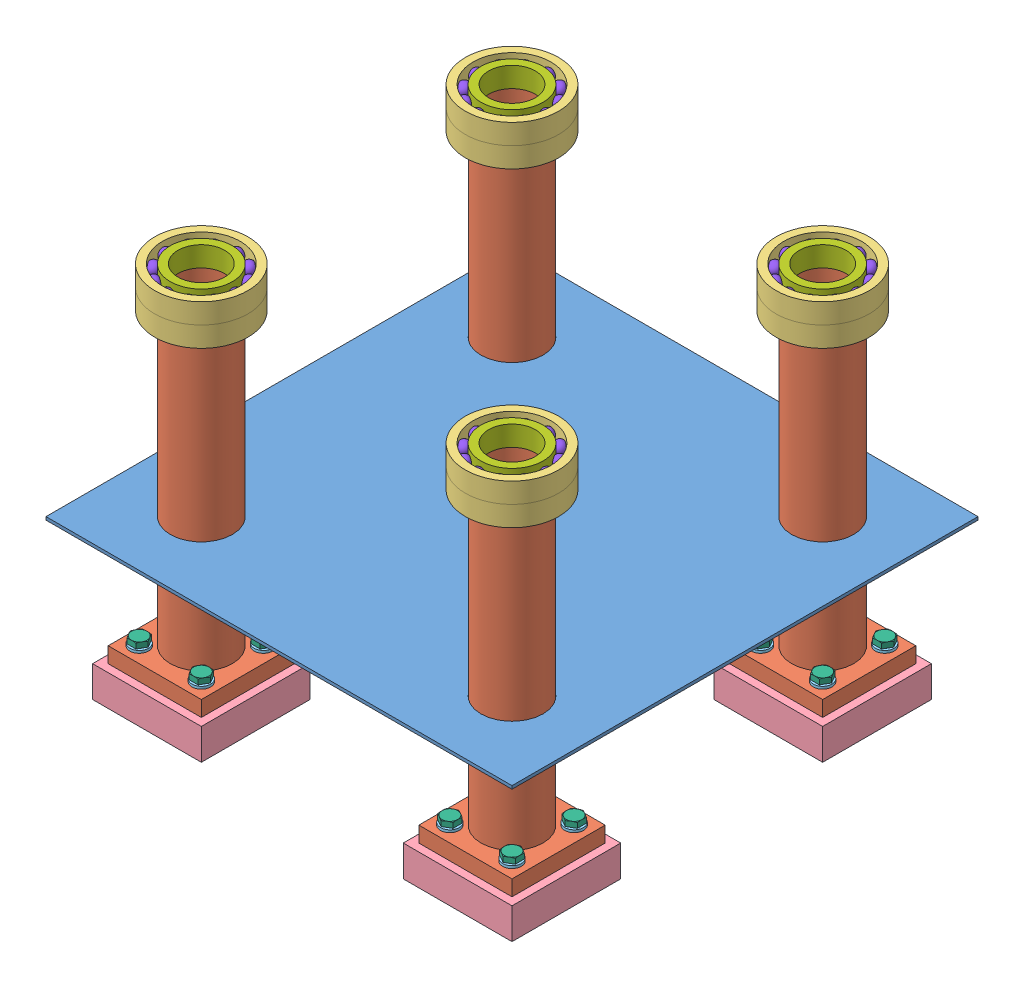
SolidWorks assembly BE101-01Z-01Z 四柱总装, configuration 默认. Lengths in mm.
Overall size (300 243 300).
113 component instances, 8 part files, 6 mates.
Components (placement in the parent):
- BE101-01Z-003 四孔平板-1: BE101-01Z-003 四孔平板 [默认] at origin size (300 2 300)
- BE101-01Z-02Z 立柱套装-1: BE101-01Z-02Z 立柱套装 [默认] at (100 -72 -100) size (70 243 70)
  - BE101-01Z-04Z 烟囱与圈-1: BE101-01Z-04Z 烟囱与圈 [默认] at origin size (60 210 60)
    - BE101-01Z-004 中空立柱-1: BE101-01Z-004 中空立柱 [默认] at origin size (60 210 60)
    - BE101-01Z-006 轴承外圈-1: BE101-01Z-006 轴承外圈 [默认] at (0 193.5 0) size (60 13 60)
  - BE101-01Z-005 四眼小板-1: BE101-01Z-005 四眼小板 [默认] at (0 -30 0) size (70 20 70)
  - plain washers--product grade c gb-1: plain washers--product grade c gb [GB_FASTENER_WASHER_SMWC 6] at (20 1.6 -20) x (1 0 0) z (0 1 0) size (12 12 1.6)
  - hex head bolts-full thread grade c gb-1: hex head bolts-full thread grade c gb [GB_FASTENER_BOLT_HHBFTC M6X20-N] at (20 5.6 -20) x (0 -1 0) z (0 0 1) size (24 11.55 10)
  - plain washers--product grade c gb-2: plain washers--product grade c gb [GB_FASTENER_WASHER_SMWC 6] at (20 1.6 20) x (1 0 0) z (0 1 0) size (12 12 1.6)
  - plain washers--product grade c gb-3: plain washers--product grade c gb [GB_FASTENER_WASHER_SMWC 6] at (-20 1.6 20) x (1 0 0) z (0 1 0) size (12 12 1.6)
  - plain washers--product grade c gb-4: plain washers--product grade c gb [GB_FASTENER_WASHER_SMWC 6] at (-20 1.6 -20) x (1 0 0) z (0 1 0) size (12 12 1.6)
  - hex head bolts-full thread grade c gb-2: hex head bolts-full thread grade c gb [GB_FASTENER_BOLT_HHBFTC M6X20-N] at (20 5.6 20) x (0 -1 0) z (0 0 1) size (24 11.55 10)
  - hex head bolts-full thread grade c gb-3: hex head bolts-full thread grade c gb [GB_FASTENER_BOLT_HHBFTC M6X20-N] at (-20 5.6 20) x (0 -1 0) z (0 0 1) size (24 11.55 10)
  - hex head bolts-full thread grade c gb-4: hex head bolts-full thread grade c gb [GB_FASTENER_BOLT_HHBFTC M6X20-N] at (-20 5.6 -20) x (0 -1 0) z (0 0 1) size (24 11.55 10)
  - BE101-01Z-03Z 滚珠轴承-1: BE101-01Z-03Z 滚珠轴承 [默认] at (0 206.5 0) size (60 13 60)
    - BE101-01Z-007 轴承内圈-1: BE101-01Z-007 轴承内圈 [默认] at origin size (40 13 40)
    - BE101-01Z-006 轴承外圈-1: BE101-01Z-006 轴承外圈 [默认] at origin size (60 13 60)
    - BE101-01Z-008 轴承滚珠-1: BE101-01Z-008 轴承滚珠 [默认] at (0 0 -22.5) size (8 8 8)
    - BE101-01Z-008 轴承滚珠-2: BE101-01Z-008 轴承滚珠 [默认] at (11.25 0 -19.4856) x (0.866025 0 0.5) z (-0.5 0 0.866025) size (8 8 8)
    - BE101-01Z-008 轴承滚珠-3: BE101-01Z-008 轴承滚珠 [默认] at (19.4856 0 -11.25) x (0.5 0 0.866025) z (-0.866025 0 0.5) size (8 8 8)
    - BE101-01Z-008 轴承滚珠-4: BE101-01Z-008 轴承滚珠 [默认] at (22.5 0 0) x (0 0 1) z (-1 0 0) size (8 8 8)
    - BE101-01Z-008 轴承滚珠-5: BE101-01Z-008 轴承滚珠 [默认] at (19.4856 0 11.25) x (-0.5 0 0.866025) z (-0.866025 0 -0.5) size (8 8 8)
    - BE101-01Z-008 轴承滚珠-6: BE101-01Z-008 轴承滚珠 [默认] at (11.25 0 19.4856) x (-0.866025 0 0.5) z (-0.5 0 -0.866025) size (8 8 8)
    - BE101-01Z-008 轴承滚珠-7: BE101-01Z-008 轴承滚珠 [默认] at (0 0 22.5) x (-1 0 0) z (0 0 -1) size (8 8 8)
    - BE101-01Z-008 轴承滚珠-8: BE101-01Z-008 轴承滚珠 [默认] at (-11.25 0 19.4856) x (-0.866025 0 -0.5) z (0.5 0 -0.866025) size (8 8 8)
    - BE101-01Z-008 轴承滚珠-9: BE101-01Z-008 轴承滚珠 [默认] at (-19.4856 0 11.25) x (-0.5 0 -0.866025) z (0.866025 0 -0.5) size (8 8 8)
    - BE101-01Z-008 轴承滚珠-10: BE101-01Z-008 轴承滚珠 [默认] at (-22.5 0 0) x (0 0 -1) z (1 0 0) size (8 8 8)
    - BE101-01Z-008 轴承滚珠-11: BE101-01Z-008 轴承滚珠 [默认] at (-19.4856 0 -11.25) x (0.5 0 -0.866025) z (0.866025 0 0.5) size (8 8 8)
    - BE101-01Z-008 轴承滚珠-12: BE101-01Z-008 轴承滚珠 [默认] at (-11.25 0 -19.4856) x (0.866025 0 -0.5) z (0.5 0 0.866025) size (8 8 8)
- BE101-01Z-02Z 立柱套装-6: BE101-01Z-02Z 立柱套装 [默认] at (100 -72 100) x (0 0 1) z (-1 0 0) size (70 243 70)
  - BE101-01Z-04Z 烟囱与圈-1: BE101-01Z-04Z 烟囱与圈 [默认] at origin size (60 210 60)
    - BE101-01Z-004 中空立柱-1: BE101-01Z-004 中空立柱 [默认] at origin size (60 210 60)
    - BE101-01Z-006 轴承外圈-1: BE101-01Z-006 轴承外圈 [默认] at (0 193.5 0) size (60 13 60)
  - BE101-01Z-005 四眼小板-1: BE101-01Z-005 四眼小板 [默认] at (0 -30 0) size (70 20 70)
  - plain washers--product grade c gb-1: plain washers--product grade c gb [GB_FASTENER_WASHER_SMWC 6] at (20 1.6 -20) x (1 0 0) z (0 1 0) size (12 12 1.6)
  - hex head bolts-full thread grade c gb-1: hex head bolts-full thread grade c gb [GB_FASTENER_BOLT_HHBFTC M6X20-N] at (20 5.6 -20) x (0 -1 0) z (0 0 1) size (24 11.55 10)
  - plain washers--product grade c gb-2: plain washers--product grade c gb [GB_FASTENER_WASHER_SMWC 6] at (20 1.6 20) x (1 0 0) z (0 1 0) size (12 12 1.6)
  - plain washers--product grade c gb-3: plain washers--product grade c gb [GB_FASTENER_WASHER_SMWC 6] at (-20 1.6 20) x (1 0 0) z (0 1 0) size (12 12 1.6)
  - plain washers--product grade c gb-4: plain washers--product grade c gb [GB_FASTENER_WASHER_SMWC 6] at (-20 1.6 -20) x (1 0 0) z (0 1 0) size (12 12 1.6)
  - hex head bolts-full thread grade c gb-2: hex head bolts-full thread grade c gb [GB_FASTENER_BOLT_HHBFTC M6X20-N] at (20 5.6 20) x (0 -1 0) z (0 0 1) size (24 11.55 10)
  - hex head bolts-full thread grade c gb-3: hex head bolts-full thread grade c gb [GB_FASTENER_BOLT_HHBFTC M6X20-N] at (-20 5.6 20) x (0 -1 0) z (0 0 1) size (24 11.55 10)
  - hex head bolts-full thread grade c gb-4: hex head bolts-full thread grade c gb [GB_FASTENER_BOLT_HHBFTC M6X20-N] at (-20 5.6 -20) x (0 -1 0) z (0 0 1) size (24 11.55 10)
  - BE101-01Z-03Z 滚珠轴承-1: BE101-01Z-03Z 滚珠轴承 [默认] at (0 206.5 0) size (60 13 60)
    - BE101-01Z-007 轴承内圈-1: BE101-01Z-007 轴承内圈 [默认] at origin size (40 13 40)
    - BE101-01Z-006 轴承外圈-1: BE101-01Z-006 轴承外圈 [默认] at origin size (60 13 60)
    - BE101-01Z-008 轴承滚珠-1: BE101-01Z-008 轴承滚珠 [默认] at (0 0 -22.5) size (8 8 8)
    - BE101-01Z-008 轴承滚珠-2: BE101-01Z-008 轴承滚珠 [默认] at (11.25 0 -19.4856) x (0.866025 0 0.5) z (-0.5 0 0.866025) size (8 8 8)
    - BE101-01Z-008 轴承滚珠-3: BE101-01Z-008 轴承滚珠 [默认] at (19.4856 0 -11.25) x (0.5 0 0.866025) z (-0.866025 0 0.5) size (8 8 8)
    - BE101-01Z-008 轴承滚珠-4: BE101-01Z-008 轴承滚珠 [默认] at (22.5 0 0) x (0 0 1) z (-1 0 0) size (8 8 8)
    - BE101-01Z-008 轴承滚珠-5: BE101-01Z-008 轴承滚珠 [默认] at (19.4856 0 11.25) x (-0.5 0 0.866025) z (-0.866025 0 -0.5) size (8 8 8)
    - BE101-01Z-008 轴承滚珠-6: BE101-01Z-008 轴承滚珠 [默认] at (11.25 0 19.4856) x (-0.866025 0 0.5) z (-0.5 0 -0.866025) size (8 8 8)
    - BE101-01Z-008 轴承滚珠-7: BE101-01Z-008 轴承滚珠 [默认] at (0 0 22.5) x (-1 0 0) z (0 0 -1) size (8 8 8)
    - BE101-01Z-008 轴承滚珠-8: BE101-01Z-008 轴承滚珠 [默认] at (-11.25 0 19.4856) x (-0.866025 0 -0.5) z (0.5 0 -0.866025) size (8 8 8)
    - BE101-01Z-008 轴承滚珠-9: BE101-01Z-008 轴承滚珠 [默认] at (-19.4856 0 11.25) x (-0.5 0 -0.866025) z (0.866025 0 -0.5) size (8 8 8)
    - BE101-01Z-008 轴承滚珠-10: BE101-01Z-008 轴承滚珠 [默认] at (-22.5 0 0) x (0 0 -1) z (1 0 0) size (8 8 8)
    - BE101-01Z-008 轴承滚珠-11: BE101-01Z-008 轴承滚珠 [默认] at (-19.4856 0 -11.25) x (0.5 0 -0.866025) z (0.866025 0 0.5) size (8 8 8)
    - BE101-01Z-008 轴承滚珠-12: BE101-01Z-008 轴承滚珠 [默认] at (-11.25 0 -19.4856) x (0.866025 0 -0.5) z (0.5 0 0.866025) size (8 8 8)
- BE101-01Z-02Z 立柱套装-7: BE101-01Z-02Z 立柱套装 [默认] at (-100 -72 100) x (-1 0 0) z (0 0 -1) size (70 243 70)
  - BE101-01Z-04Z 烟囱与圈-1: BE101-01Z-04Z 烟囱与圈 [默认] at origin size (60 210 60)
    - BE101-01Z-004 中空立柱-1: BE101-01Z-004 中空立柱 [默认] at origin size (60 210 60)
    - BE101-01Z-006 轴承外圈-1: BE101-01Z-006 轴承外圈 [默认] at (0 193.5 0) size (60 13 60)
  - BE101-01Z-005 四眼小板-1: BE101-01Z-005 四眼小板 [默认] at (0 -30 0) size (70 20 70)
  - plain washers--product grade c gb-1: plain washers--product grade c gb [GB_FASTENER_WASHER_SMWC 6] at (20 1.6 -20) x (1 0 0) z (0 1 0) size (12 12 1.6)
  - hex head bolts-full thread grade c gb-1: hex head bolts-full thread grade c gb [GB_FASTENER_BOLT_HHBFTC M6X20-N] at (20 5.6 -20) x (0 -1 0) z (0 0 1) size (24 11.55 10)
  - plain washers--product grade c gb-2: plain washers--product grade c gb [GB_FASTENER_WASHER_SMWC 6] at (20 1.6 20) x (1 0 0) z (0 1 0) size (12 12 1.6)
  - plain washers--product grade c gb-3: plain washers--product grade c gb [GB_FASTENER_WASHER_SMWC 6] at (-20 1.6 20) x (1 0 0) z (0 1 0) size (12 12 1.6)
  - plain washers--product grade c gb-4: plain washers--product grade c gb [GB_FASTENER_WASHER_SMWC 6] at (-20 1.6 -20) x (1 0 0) z (0 1 0) size (12 12 1.6)
  - hex head bolts-full thread grade c gb-2: hex head bolts-full thread grade c gb [GB_FASTENER_BOLT_HHBFTC M6X20-N] at (20 5.6 20) x (0 -1 0) z (0 0 1) size (24 11.55 10)
  - hex head bolts-full thread grade c gb-3: hex head bolts-full thread grade c gb [GB_FASTENER_BOLT_HHBFTC M6X20-N] at (-20 5.6 20) x (0 -1 0) z (0 0 1) size (24 11.55 10)
  - hex head bolts-full thread grade c gb-4: hex head bolts-full thread grade c gb [GB_FASTENER_BOLT_HHBFTC M6X20-N] at (-20 5.6 -20) x (0 -1 0) z (0 0 1) size (24 11.55 10)
  - BE101-01Z-03Z 滚珠轴承-1: BE101-01Z-03Z 滚珠轴承 [默认] at (0 206.5 0) size (60 13 60)
    - BE101-01Z-007 轴承内圈-1: BE101-01Z-007 轴承内圈 [默认] at origin size (40 13 40)
    - BE101-01Z-006 轴承外圈-1: BE101-01Z-006 轴承外圈 [默认] at origin size (60 13 60)
    - BE101-01Z-008 轴承滚珠-1: BE101-01Z-008 轴承滚珠 [默认] at (0 0 -22.5) size (8 8 8)
    - BE101-01Z-008 轴承滚珠-2: BE101-01Z-008 轴承滚珠 [默认] at (11.25 0 -19.4856) x (0.866025 0 0.5) z (-0.5 0 0.866025) size (8 8 8)
    - BE101-01Z-008 轴承滚珠-3: BE101-01Z-008 轴承滚珠 [默认] at (19.4856 0 -11.25) x (0.5 0 0.866025) z (-0.866025 0 0.5) size (8 8 8)
    - BE101-01Z-008 轴承滚珠-4: BE101-01Z-008 轴承滚珠 [默认] at (22.5 0 0) x (0 0 1) z (-1 0 0) size (8 8 8)
    - BE101-01Z-008 轴承滚珠-5: BE101-01Z-008 轴承滚珠 [默认] at (19.4856 0 11.25) x (-0.5 0 0.866025) z (-0.866025 0 -0.5) size (8 8 8)
    - BE101-01Z-008 轴承滚珠-6: BE101-01Z-008 轴承滚珠 [默认] at (11.25 0 19.4856) x (-0.866025 0 0.5) z (-0.5 0 -0.866025) size (8 8 8)
    - BE101-01Z-008 轴承滚珠-7: BE101-01Z-008 轴承滚珠 [默认] at (0 0 22.5) x (-1 0 0) z (0 0 -1) size (8 8 8)
    - BE101-01Z-008 轴承滚珠-8: BE101-01Z-008 轴承滚珠 [默认] at (-11.25 0 19.4856) x (-0.866025 0 -0.5) z (0.5 0 -0.866025) size (8 8 8)
    - BE101-01Z-008 轴承滚珠-9: BE101-01Z-008 轴承滚珠 [默认] at (-19.4856 0 11.25) x (-0.5 0 -0.866025) z (0.866025 0 -0.5) size (8 8 8)
    - BE101-01Z-008 轴承滚珠-10: BE101-01Z-008 轴承滚珠 [默认] at (-22.5 0 0) x (0 0 -1) z (1 0 0) size (8 8 8)
    - BE101-01Z-008 轴承滚珠-11: BE101-01Z-008 轴承滚珠 [默认] at (-19.4856 0 -11.25) x (0.5 0 -0.866025) z (0.866025 0 0.5) size (8 8 8)
    - BE101-01Z-008 轴承滚珠-12: BE101-01Z-008 轴承滚珠 [默认] at (-11.25 0 -19.4856) x (0.866025 0 -0.5) z (0.5 0 0.866025) size (8 8 8)
- BE101-01Z-02Z 立柱套装-8: BE101-01Z-02Z 立柱套装 [默认] at (-100 -72 -100) x (0 0 -1) z (1 0 0) size (70 243 70)
  - BE101-01Z-04Z 烟囱与圈-1: BE101-01Z-04Z 烟囱与圈 [默认] at origin size (60 210 60)
    - BE101-01Z-004 中空立柱-1: BE101-01Z-004 中空立柱 [默认] at origin size (60 210 60)
    - BE101-01Z-006 轴承外圈-1: BE101-01Z-006 轴承外圈 [默认] at (0 193.5 0) size (60 13 60)
  - BE101-01Z-005 四眼小板-1: BE101-01Z-005 四眼小板 [默认] at (0 -30 0) size (70 20 70)
  - plain washers--product grade c gb-1: plain washers--product grade c gb [GB_FASTENER_WASHER_SMWC 6] at (20 1.6 -20) x (1 0 0) z (0 1 0) size (12 12 1.6)
  - hex head bolts-full thread grade c gb-1: hex head bolts-full thread grade c gb [GB_FASTENER_BOLT_HHBFTC M6X20-N] at (20 5.6 -20) x (0 -1 0) z (0 0 1) size (24 11.55 10)
  - plain washers--product grade c gb-2: plain washers--product grade c gb [GB_FASTENER_WASHER_SMWC 6] at (20 1.6 20) x (1 0 0) z (0 1 0) size (12 12 1.6)
  - plain washers--product grade c gb-3: plain washers--product grade c gb [GB_FASTENER_WASHER_SMWC 6] at (-20 1.6 20) x (1 0 0) z (0 1 0) size (12 12 1.6)
  - plain washers--product grade c gb-4: plain washers--product grade c gb [GB_FASTENER_WASHER_SMWC 6] at (-20 1.6 -20) x (1 0 0) z (0 1 0) size (12 12 1.6)
  - hex head bolts-full thread grade c gb-2: hex head bolts-full thread grade c gb [GB_FASTENER_BOLT_HHBFTC M6X20-N] at (20 5.6 20) x (0 -1 0) z (0 0 1) size (24 11.55 10)
  - hex head bolts-full thread grade c gb-3: hex head bolts-full thread grade c gb [GB_FASTENER_BOLT_HHBFTC M6X20-N] at (-20 5.6 20) x (0 -1 0) z (0 0 1) size (24 11.55 10)
  - hex head bolts-full thread grade c gb-4: hex head bolts-full thread grade c gb [GB_FASTENER_BOLT_HHBFTC M6X20-N] at (-20 5.6 -20) x (0 -1 0) z (0 0 1) size (24 11.55 10)
  - BE101-01Z-03Z 滚珠轴承-1: BE101-01Z-03Z 滚珠轴承 [默认] at (0 206.5 0) size (60 13 60)
    - BE101-01Z-007 轴承内圈-1: BE101-01Z-007 轴承内圈 [默认] at origin size (40 13 40)
    - BE101-01Z-006 轴承外圈-1: BE101-01Z-006 轴承外圈 [默认] at origin size (60 13 60)
    - BE101-01Z-008 轴承滚珠-1: BE101-01Z-008 轴承滚珠 [默认] at (0 0 -22.5) size (8 8 8)
    - BE101-01Z-008 轴承滚珠-2: BE101-01Z-008 轴承滚珠 [默认] at (11.25 0 -19.4856) x (0.866025 0 0.5) z (-0.5 0 0.866025) size (8 8 8)
    - BE101-01Z-008 轴承滚珠-3: BE101-01Z-008 轴承滚珠 [默认] at (19.4856 0 -11.25) x (0.5 0 0.866025) z (-0.866025 0 0.5) size (8 8 8)
    - BE101-01Z-008 轴承滚珠-4: BE101-01Z-008 轴承滚珠 [默认] at (22.5 0 0) x (0 0 1) z (-1 0 0) size (8 8 8)
    - BE101-01Z-008 轴承滚珠-5: BE101-01Z-008 轴承滚珠 [默认] at (19.4856 0 11.25) x (-0.5 0 0.866025) z (-0.866025 0 -0.5) size (8 8 8)
    - BE101-01Z-008 轴承滚珠-6: BE101-01Z-008 轴承滚珠 [默认] at (11.25 0 19.4856) x (-0.866025 0 0.5) z (-0.5 0 -0.866025) size (8 8 8)
    - BE101-01Z-008 轴承滚珠-7: BE101-01Z-008 轴承滚珠 [默认] at (0 0 22.5) x (-1 0 0) z (0 0 -1) size (8 8 8)
    - BE101-01Z-008 轴承滚珠-8: BE101-01Z-008 轴承滚珠 [默认] at (-11.25 0 19.4856) x (-0.866025 0 -0.5) z (0.5 0 -0.866025) size (8 8 8)
    - BE101-01Z-008 轴承滚珠-9: BE101-01Z-008 轴承滚珠 [默认] at (-19.4856 0 11.25) x (-0.5 0 -0.866025) z (0.866025 0 -0.5) size (8 8 8)
    - BE101-01Z-008 轴承滚珠-10: BE101-01Z-008 轴承滚珠 [默认] at (-22.5 0 0) x (0 0 -1) z (1 0 0) size (8 8 8)
    - BE101-01Z-008 轴承滚珠-11: BE101-01Z-008 轴承滚珠 [默认] at (-19.4856 0 -11.25) x (0.5 0 -0.866025) z (0.866025 0 0.5) size (8 8 8)
    - BE101-01Z-008 轴承滚珠-12: BE101-01Z-008 轴承滚珠 [默认] at (-11.25 0 -19.4856) x (0.866025 0 -0.5) z (0.5 0 0.866025) size (8 8 8)
Mates (geometry in assembly coordinates):
- 重合1: coincident aligned: plane of BE101-01Z-003 四孔平板-1 through (0 0 0) normal (0 0 1)
- 同心1: concentric anti-aligned: cylinder of BE101-01Z-003 四孔平板-1 through (100 -2 -100) axis (0 1 0) radius 20; cylinder of BE101-01Z-02Z 立柱套装-1/BE101-01Z-04Z 烟囱与圈-1/BE101-01Z-004 中空立柱-1 through (100 128 -100) axis (0 -1 0) radius 20
- 距离1: distance = 100 mm aligned: plane of BE101-01Z-02Z 立柱套装-1/BE101-01Z-005 四眼小板-1 through (100 -102 -100) normal (0 -1 0); plane of BE101-01Z-003 四孔平板-1 through (0 -2 0) normal (0 -1 0)
- 重合5: coincident aligned: plane of BE101-01Z-003 四孔平板-1 through (0 0 0) normal (0 0 1)
- 重合6: coincident aligned: plane of BE101-01Z-003 四孔平板-1 through (0 0 0) normal (0 1 0)
- 重合7: coincident aligned: plane of BE101-01Z-003 四孔平板-1 through (0 0 0) normal (1 0 0)
